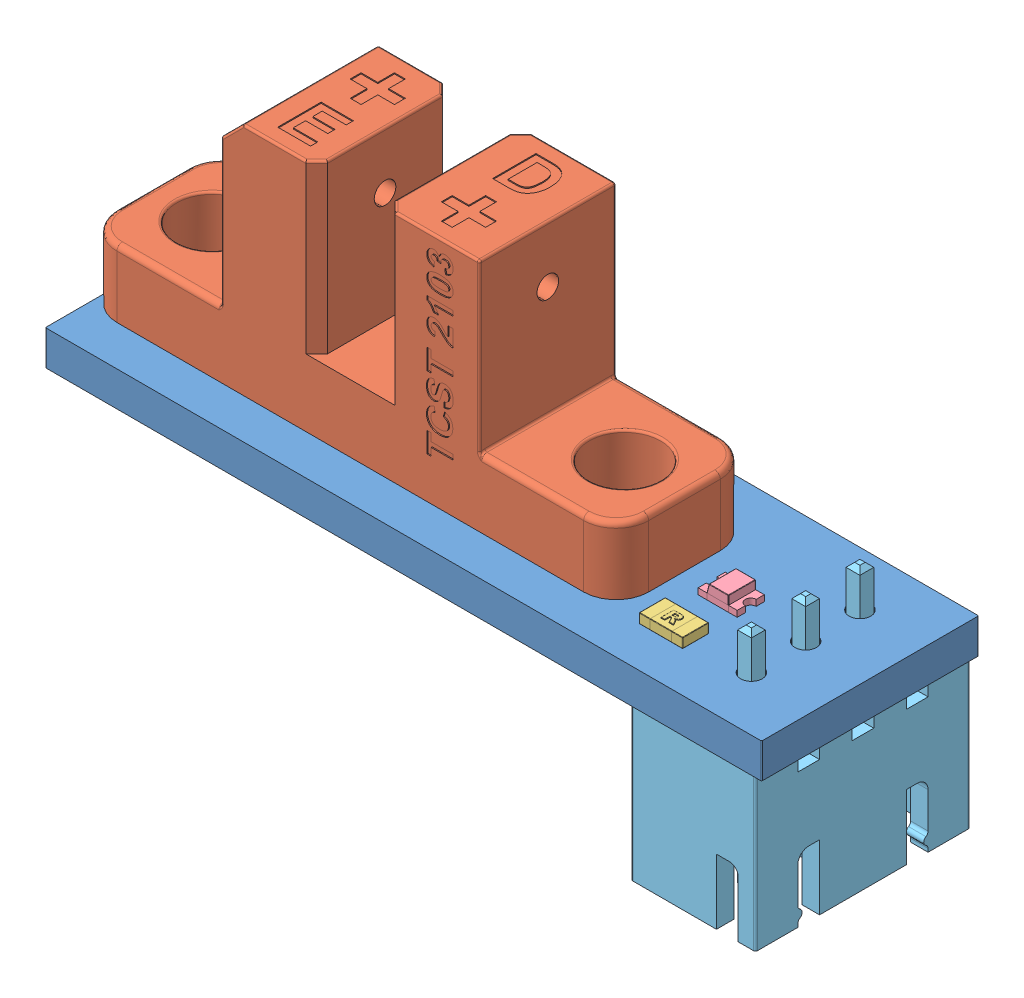
SolidWorks assembly Optical Endstop Switch, configuration По умолчанию. Lengths in mm.
Overall size (33.05 19.4 10).
7 component instances, 5 part files, 20 mates.
Components (placement in the parent):
- Board^Optical Endstop Switch-1: Board^Optical Endstop Switch [По умолчанию] at origin size (33 1.67 10) (virtual)
- TCST2103^Optical Endstop Switch-1: TCST2103^Optical Endstop Switch [По умолчанию] at (-0.05 1.6 -8.15) size (24.5 13.8 6.38) (virtual)
- RES_0805^Optical Endstop Switch-1: RES_0805^Optical Endstop Switch [По умолчанию] at (25.5 1.6 -1.86) size (2 0.49 1.2) (virtual)
- RES_0805^Optical Endstop Switch-2: RES_0805^Optical Endstop Switch [По умолчанию] at (13.25 0 -2.2) x (-1 0 0) z (0 0 1) size (2 0.49 1.2) (virtual)
- LED_0805_Green^Optical Endstop Switch-1: LED_0805_Green^Optical Endstop Switch [По умолчанию] at (27.5 1.6 -5.625) x (-1 0 0) z (0 0 -1) size (1.8 0.68 1.25) (virtual)
- RES_0805^Optical Endstop Switch-3: RES_0805^Optical Endstop Switch [По умолчанию] at (13.25 0 -6.6) x (-1 0 0) z (0 0 1) size (2 0.49 1.2) (virtual)
- JST-XH-3A^Optical Endstop Switch-1: JST-XH-3A^Optical Endstop Switch [По умолчанию] at (32.67 0 -9.95) x (0 0 1) z (1 0 0) size (9.9 10.5 5.75) (virtual)
Mates (geometry in assembly coordinates):
- Концентричный1: concentric: cylinder of Board^Optical Endstop Switch-1 through (8.4 1.6 -3.73) axis (0 -1 0) radius 0.4; cylinder of TCST2103^Optical Endstop Switch-1 through (8.4 -1.4 -3.73) axis (0 1 0) radius 0.3
- Концентричный2: concentric: cylinder of Board^Optical Endstop Switch-1 through (16 1.6 -6.27) axis (0 -1 0) radius 0.4; cylinder of TCST2103^Optical Endstop Switch-1 through (16 -1.4 -6.27) axis (0 1 0) radius 0.3
- Совпадение1: coincident: plane of Board^Optical Endstop Switch-1 through (0 1.6 0) normal (0 1 0); plane of TCST2103^Optical Endstop Switch-1 through (-0.05 1.6 -1.85) normal (0 -1 0)
- Совпадение2: coincident: plane of Board^Optical Endstop Switch-1 through (0 1.6 0) normal (0 1 0); plane of RES_0805^Optical Endstop Switch-1 through (27 1.6 -1.86) normal (0 -1 0)
- Совпадение3: coincident: plane of Board^Optical Endstop Switch-1 through (0 1.6 0) normal (0 1 0); plane of LED_0805_Green^Optical Endstop Switch-1 through (26.1 1.6 -5.625) normal (0 -1 0)
- Совпадение4: coincident: plane of RES_0805^Optical Endstop Switch-1 through (27.5 1.6 -1.86) normal (1 0 0); plane of LED_0805_Green^Optical Endstop Switch-1 through (27.5 1.6 -5.625) normal (1 0 0)
- Совпадение5: coincident: plane of Board^Optical Endstop Switch-1 through (0 0 0) normal (0 -1 0); plane of RES_0805^Optical Endstop Switch-2 through (11.75 0 -2.2) normal (0 1 0)
- Совпадение6: coincident: plane of Board^Optical Endstop Switch-1 through (0 0 0) normal (0 -1 0); plane of RES_0805^Optical Endstop Switch-3 through (11.75 0 -6.6) normal (0 1 0)
- Параллельность1: parallel: plane of Board^Optical Endstop Switch-1 through (0 1.6 -10) normal (0 0 -1); plane of RES_0805^Optical Endstop Switch-3 through (11.75 0 -7.8) normal (0 0 -1)
- Параллельность2: parallel: plane of RES_0805^Optical Endstop Switch-2 through (11.75 0 -3.4) normal (0 0 -1); plane of RES_0805^Optical Endstop Switch-3 through (11.75 -0.45 -6.6) normal (0 0 1)
- Совпадение9: coincident: plane of RES_0805^Optical Endstop Switch-2 through (11.25 0 -2.2) normal (-1 0 0); plane of RES_0805^Optical Endstop Switch-3 through (11.25 0 -6.6) normal (-1 0 0)
- Расстояние1: distance = 2.2 mm: plane of RES_0805^Optical Endstop Switch-2 through (11.75 -0.45 -2.2) normal (0 0 1); plane of Board^Optical Endstop Switch-1 through (0 1.6 0) normal (0 0 1)
- Расстояние2: distance = 2.2 mm: plane of RES_0805^Optical Endstop Switch-3 through (11.75 0 -7.8) normal (0 0 -1); plane of Board^Optical Endstop Switch-1 through (0 1.6 -10) normal (0 0 -1)
- Расстояние3: distance = 2.55 mm: plane of RES_0805^Optical Endstop Switch-2 through (11.25 0 -2.2) normal (-1 0 0); cylinder of TCST2103^Optical Endstop Switch-1 through (8.4 -1.4 -3.73) axis (0 1 0) radius 0.3
- Расстояние4: distance = 1.86 mm: plane of RES_0805^Optical Endstop Switch-1 through (27 2.05 -1.86) normal (0 0 1); plane of Board^Optical Endstop Switch-1 through (0 1.6 0) normal (0 0 1)
- Расстояние5: distance = 4.375 mm: plane of LED_0805_Green^Optical Endstop Switch-1 through (26.1 1.6 -4.375) normal (0 0 1); plane of Board^Optical Endstop Switch-1 through (0 1.6 0) normal (0 0 1)
- Расстояние6: distance = 5.5 mm: plane of RES_0805^Optical Endstop Switch-1 through (27.5 1.6 -1.86) normal (1 0 0); plane of Board^Optical Endstop Switch-1 through (33 1.6 0) normal (1 0 0)
- Совпадение10: coincident: plane of Board^Optical Endstop Switch-1 through (0 0 0) normal (0 -1 0); plane of JST-XH-3A^Optical Endstop Switch-1 through (32.67 0 -9.95) normal (0 1 0)
- Расстояние8: distance = 0.33 mm: plane of Board^Optical Endstop Switch-1 through (33 1.6 0) normal (1 0 0); plane of JST-XH-3A^Optical Endstop Switch-1 through (32.67 -7 -9.95) normal (1 0 0)
- Расстояние7: distance = 0.05 mm: plane of JST-XH-3A^Optical Endstop Switch-1 through (32.67 -7 -0.05) normal (0 0 1); plane of Board^Optical Endstop Switch-1 through (0 1.6 0) normal (0 0 1)
